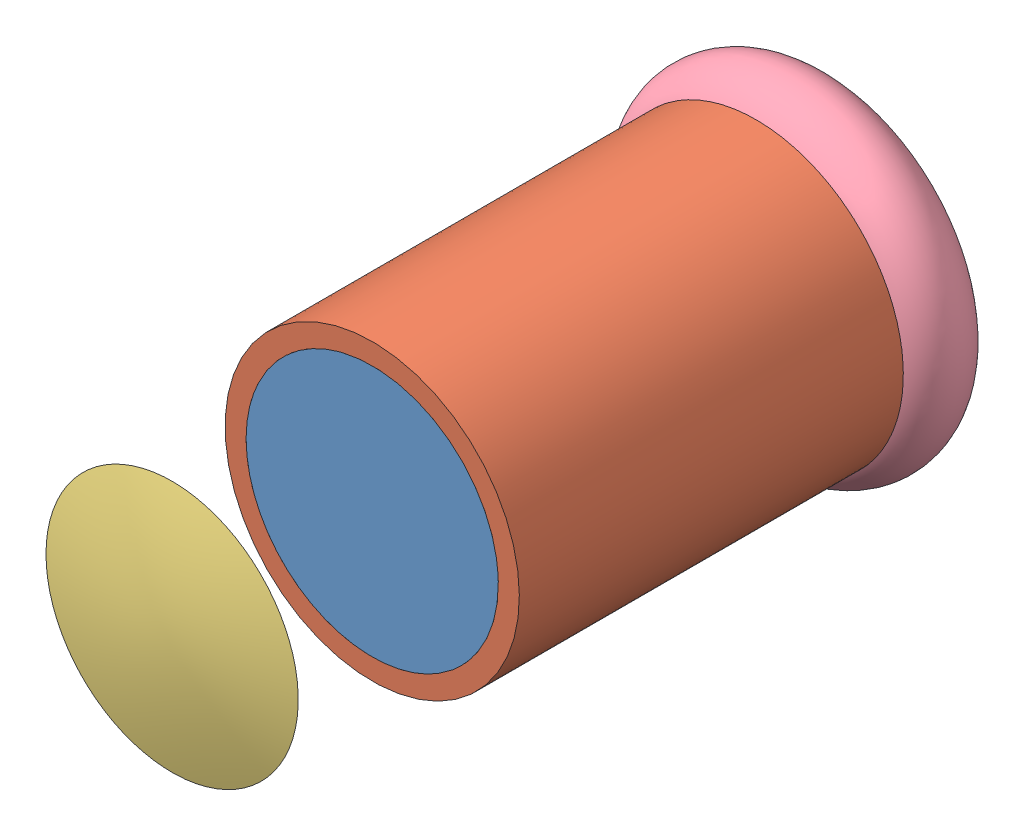
SolidWorks assembly 苹果甜度检测, configuration 默认. Lengths in mm.
Overall size (45.74 45.74 81.3).
4 component instances, 4 part files, 3 mates.
Components (placement in the parent):
- 镜头适配片-1: 镜头适配片 [默认] at (-73.4351 49.5009 -52.4056) size (30 30 5)
- 筒-2: 筒 [默认] at (-73.4351 49.5009 -47.4056) x (-0.923728 -0.383049 0) z (-0.383049 0.923728 0) size (35 50 35)
- 透镜-1: 透镜 [默认] at (-73.4351 49.5009 -23.6054) size (30 30 5)
- 下-1: 下 [默认] at (-73.4351 49.5009 -97.4056) size (40 40 10)
Mates (geometry in assembly coordinates):
- 重合2: coincident: circle of assembly; circle of assembly; circle of 镜头适配片-1; circle of 筒-2
- 同心4: concentric: circle of assembly; circle of assembly; circle of 筒-2; circle of 透镜-1
- 重合3: coincident: circle of assembly; circle of assembly; circle of 筒-2; circle of 下-1
